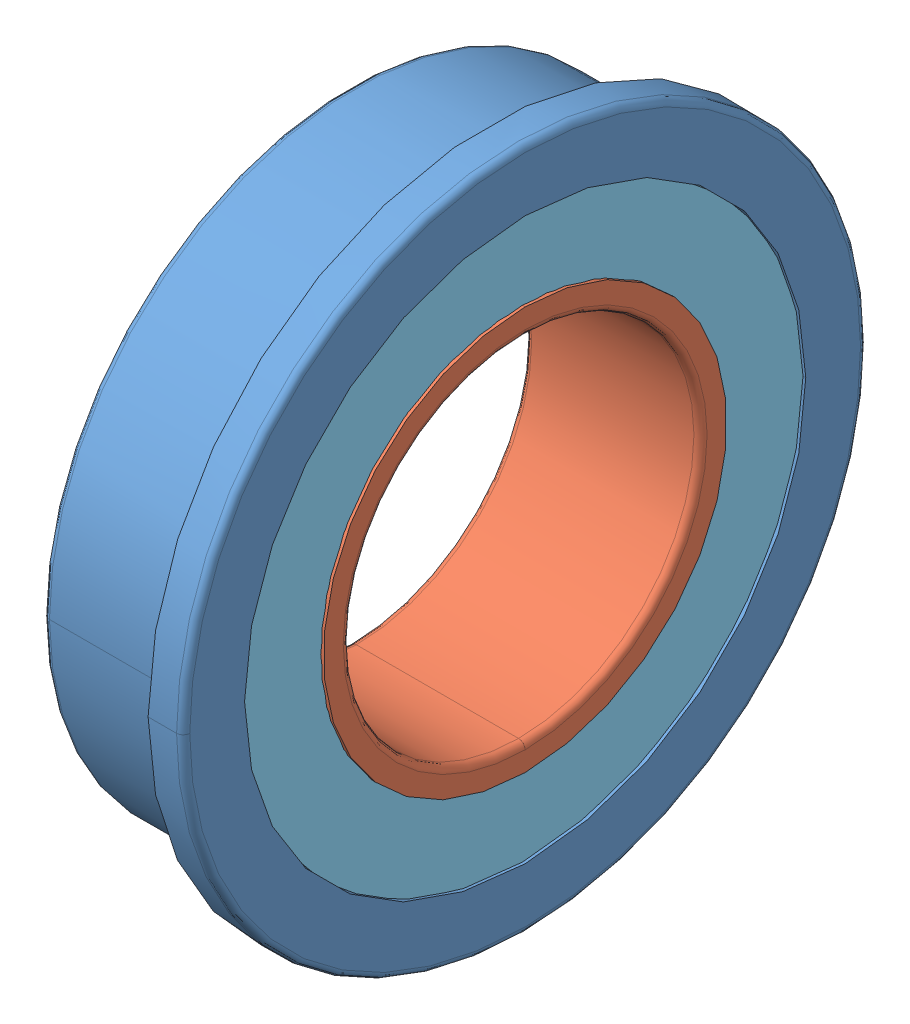
SolidWorks assembly MF148ZZ, configuration Default. Lengths in mm.
Overall size (4 15.6 15.6).
18 component instances, 5 part files, 0 mates.
Components (placement in the parent):
- _MF148ZZ_Outer_Ring_2-1: _MF148ZZ_Outer_Ring_2 [Default] at origin size (4 15.6 15.6)
- _MF148ZZ_Inner_Ring_4-1: _MF148ZZ_Inner_Ring_4 [Default] x (1 0 0) z (0 -1 0) size (4 9.86 9.86)
- _MF148ZZ_Shield1_6-1: _MF148ZZ_Shield1_6 [Default] at (0.5 0 0) x (-1 0 0) z (0 -1 0) size (0.19 12.8 12.8)
- _MF148ZZ_Ball_8-1: _MF148ZZ_Ball_8 [Default] at (2 0 5.5) x (1 0 0) z (0 -1 0) size (1.8 1.8 1.8)
- _MF148ZZ_Ball_8-2: _MF148ZZ_Ball_8 [Default] at (2 -2.3864 4.9553) x (1 0 0) z (0 -1 0) size (1.8 1.8 1.8)
- _MF148ZZ_Ball_8-3: _MF148ZZ_Ball_8 [Default] at (2 -4.3001 3.4292) x (1 0 0) z (0 -1 0) size (1.8 1.8 1.8)
- _MF148ZZ_Ball_8-4: _MF148ZZ_Ball_8 [Default] at (2 -5.3621 1.2239) x (1 0 0) z (0 -1 0) size (1.8 1.8 1.8)
- _MF148ZZ_Ball_8-5: _MF148ZZ_Ball_8 [Default] at (2 -5.3621 -1.2239) x (1 0 0) z (0 -1 0) size (1.8 1.8 1.8)
- _MF148ZZ_Ball_8-6: _MF148ZZ_Ball_8 [Default] at (2 -4.3001 -3.4292) x (1 0 0) z (0 -1 0) size (1.8 1.8 1.8)
- _MF148ZZ_Ball_8-7: _MF148ZZ_Ball_8 [Default] at (2 -2.3864 -4.9553) x (1 0 0) z (0 -1 0) size (1.8 1.8 1.8)
- _MF148ZZ_Ball_8-8: _MF148ZZ_Ball_8 [Default] at (2 0 -5.5) x (1 0 0) z (0 -1 0) size (1.8 1.8 1.8)
- _MF148ZZ_Ball_8-9: _MF148ZZ_Ball_8 [Default] at (2 2.3864 -4.9553) x (1 0 0) z (0 -1 0) size (1.8 1.8 1.8)
- _MF148ZZ_Ball_8-10: _MF148ZZ_Ball_8 [Default] at (2 4.3001 -3.4292) x (1 0 0) z (0 -1 0) size (1.8 1.8 1.8)
- _MF148ZZ_Ball_8-11: _MF148ZZ_Ball_8 [Default] at (2 5.3621 -1.2239) x (1 0 0) z (0 -1 0) size (1.8 1.8 1.8)
- _MF148ZZ_Ball_8-12: _MF148ZZ_Ball_8 [Default] at (2 5.3621 1.2239) x (1 0 0) z (0 -1 0) size (1.8 1.8 1.8)
- _MF148ZZ_Ball_8-13: _MF148ZZ_Ball_8 [Default] at (2 4.3001 3.4292) x (1 0 0) z (0 -1 0) size (1.8 1.8 1.8)
- _MF148ZZ_Ball_8-14: _MF148ZZ_Ball_8 [Default] at (2 2.3864 4.9553) x (1 0 0) z (0 -1 0) size (1.8 1.8 1.8)
- _MF148ZZ_Shield2_23-1: _MF148ZZ_Shield2_23 [Default] at origin size (0.19 12.8 12.8)
